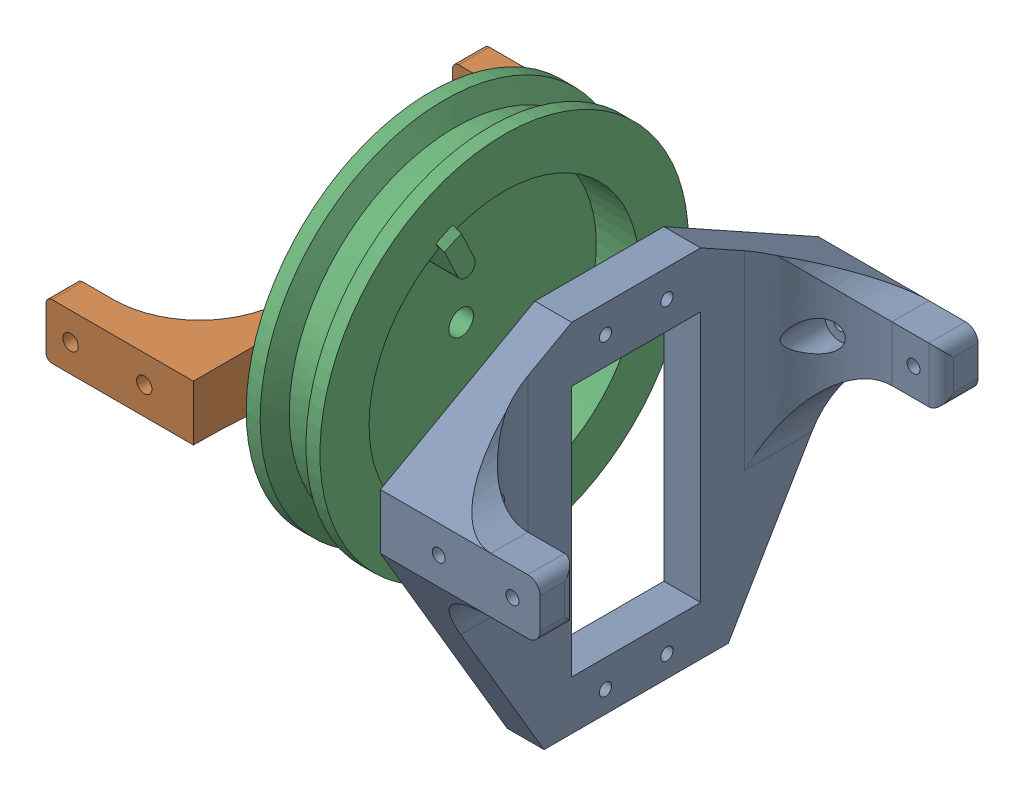
SolidWorks assembly pulley, configuration Default. Lengths in mm.
Overall size (80.5 79.8 79.8).
3 component instances, 3 part files, 6 mates.
Components (placement in the parent):
- bracket_servo_pulley-1: bracket_servo_pulley [Default] at (-17.6782 6.3653 4.3345) size (26 58 71.3)
- bracket_wheel_pulley-1: bracket_wheel_pulley [Default] at (-52.1782 6.3653 4.3345) x (0 0 -1) z (1 0 0) size (71.2 13.5 24)
- haspeltje-1: haspeltje [Default] at (-45.1782 6.3653 4.3345) x (0 0.424708 -0.90533) z (0 -0.90533 -0.424708) size (60 13 60)
Mates (geometry in assembly coordinates):
- Concentric1: concentric: cylinder of assembly; point of bracket_servo_pulley-1; cylinder of bracket_wheel_pulley-1 through (-48.1782 6.3653 4.3345) axis (-1 0 0) radius 2
- Parallel1: parallel aligned: plane of bracket_servo_pulley-1 through (-11.6782 25.8653 4.3345) normal (0 1 0); plane of bracket_wheel_pulley-1 through (-48.1782 11.8653 4.3345) normal (0 1 0)
- Parallel2: parallel anti-aligned: plane of bracket_servo_pulley-1 through (-11.6782 6.3653 -31.3155) normal (0 0 -1); plane of bracket_wheel_pulley-1 through (-48.1782 6.3653 39.9345) normal (0 0 1)
- Distance1: distance = 30.5 mm anti-aligned: plane of bracket_servo_pulley-1 through (-17.6782 6.3653 4.3345) normal (-1 0 0); plane of bracket_wheel_pulley-1 through (-48.1782 6.3653 4.3345) normal (1 0 0)
- Concentric2: concentric: cylinder of bracket_wheel_pulley-1 through (-48.1782 6.3653 4.3345) axis (-1 0 0) radius 2; cylinder of haspeltje-1 through (-43.1782 6.3653 4.3345) axis (-1 0 0) radius 2
- Distance2: distance = 3 mm anti-aligned: plane of haspeltje-1 through (-45.1782 6.3653 4.3345) normal (-1 0 0); plane of bracket_wheel_pulley-1 through (-48.1782 6.3653 4.3345) normal (1 0 0)
